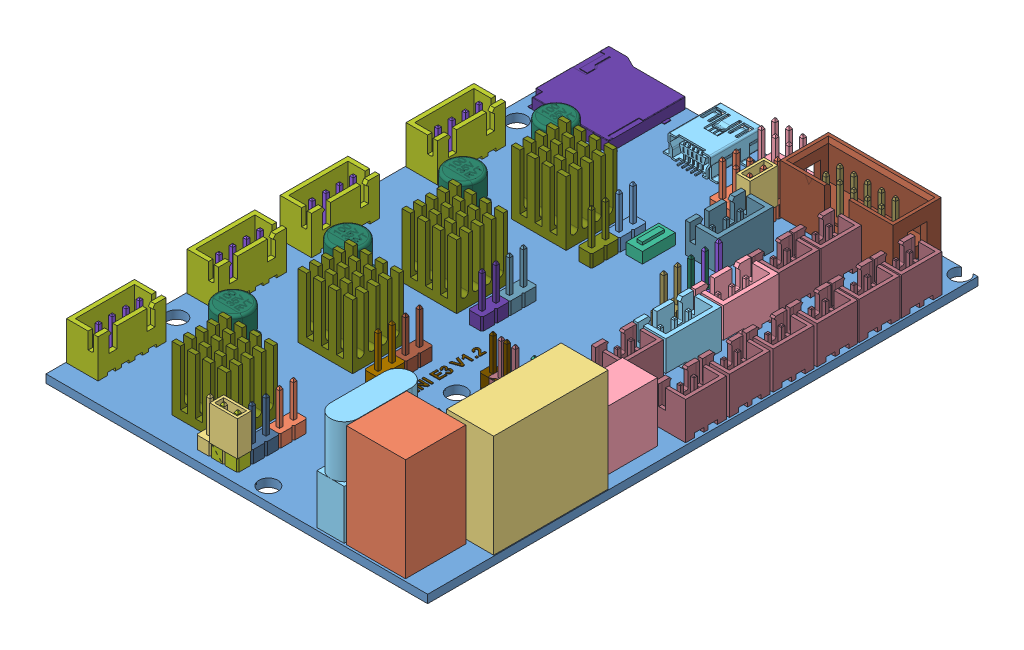
SolidWorks assembly BTT SKR MINI E3 V1.2 - 2020 DR.Phil3D v1, configuration BTT SKR MINI E3 V1.2 - 2020 DR.Phil3D v1. Lengths in mm.
Overall size (69.7 22.28 101.21).
95 component instances, 41 part files, 0 mates.
Components (placement in the parent):
- SKR Mini E3 1.2-1: SKR Mini E3 1.2 [SKR Mini E3 1.2] at (0.4313 -1.6126 -0.8701) size (69.7 20.32 100.5)
  - PCB-1: PCB [PCB] at origin size (69.7 1.5 100.5)
  - Power IN-1: Power IN [Power IN] at (-14.6583 0 -3.0665) size (10.79 18.82 11)
  - Power & Bed -1: Power & Bed  [Power & Bed ] at (-15.6583 0 -3.0665) size (8.58 18.82 20.9)
  - E0-1: E0 [E0] at (-15.6583 0 -3.0665) size (6.36 10.82 10)
  - Fuse-1: Fuse [Fuse] at (-14.6583 0 -3.0665) size (5 18.48 14.84)
  - Reset-1: Reset [Reset] at (-4.0633 0 9.9288) size (3 2.5 6)
- 4 pin Header-1: 4 pin Header [4 pin Header] at (-25.3481 -5.4688 -25.9996) x (0 0 1) z (-1 0 0) size (12.4 10.4 5.75)
  - B4B-XH-A (BODY)-1: B4B-XH-A (BODY) [B4B-XH-A (BODY)] at (1.9192 5.3562 13.8157) size (12.4 7 5.75)
  - B4B-XH-A (PIN)-1: B4B-XH-A (PIN) [B4B-XH-A (PIN)] at (5.6692 12.3562 13.2907) x (-1 0 0) z (0 0 1) size (0.64 10.4 0.64)
  - B4B-XH-A (PIN)-2: B4B-XH-A (PIN) [B4B-XH-A (PIN)] at (3.1692 12.3562 13.2907) x (-1 0 0) z (0 0 1) size (0.64 10.4 0.64)
  - B4B-XH-A (PIN)-3: B4B-XH-A (PIN) [B4B-XH-A (PIN)] at (0.6692 12.3562 13.2907) x (-1 0 0) z (0 0 1) size (0.64 10.4 0.64)
  - B4B-XH-A (PIN)-4: B4B-XH-A (PIN) [B4B-XH-A (PIN)] at (-1.8308 12.3562 13.2907) x (-1 0 0) z (0 0 1) size (0.64 10.4 0.64)
- 4 pin Header_1-1: 4 pin Header_1 [4 pin Header_1] at (-25.3481 -5.4688 -2.9996) x (0 0 1) z (-1 0 0) size (12.4 10.4 5.75)
  - B4B-XH-A (BODY)-1: B4B-XH-A (BODY) [B4B-XH-A (BODY)] at (1.9192 5.3562 13.8157) size (12.4 7 5.75)
  - B4B-XH-A (PIN)-1: B4B-XH-A (PIN) [B4B-XH-A (PIN)] at (5.6692 12.3562 13.2907) x (-1 0 0) z (0 0 1) size (0.64 10.4 0.64)
  - B4B-XH-A (PIN)-2: B4B-XH-A (PIN) [B4B-XH-A (PIN)] at (3.1692 12.3562 13.2907) x (-1 0 0) z (0 0 1) size (0.64 10.4 0.64)
  - B4B-XH-A (PIN)-3: B4B-XH-A (PIN) [B4B-XH-A (PIN)] at (0.6692 12.3562 13.2907) x (-1 0 0) z (0 0 1) size (0.64 10.4 0.64)
  - B4B-XH-A (PIN)-4: B4B-XH-A (PIN) [B4B-XH-A (PIN)] at (-1.8308 12.3562 13.2907) x (-1 0 0) z (0 0 1) size (0.64 10.4 0.64)
- 4 pin Header_2-1: 4 pin Header_2 [4 pin Header_2] at (-25.3481 -5.4688 14.0004) x (0 0 1) z (-1 0 0) size (12.4 10.4 5.75)
  - B4B-XH-A (BODY)-1: B4B-XH-A (BODY) [B4B-XH-A (BODY)] at (1.9192 5.3562 13.8157) size (12.4 7 5.75)
  - B4B-XH-A (PIN)-1: B4B-XH-A (PIN) [B4B-XH-A (PIN)] at (5.6692 12.3562 13.2907) x (-1 0 0) z (0 0 1) size (0.64 10.4 0.64)
  - B4B-XH-A (PIN)-2: B4B-XH-A (PIN) [B4B-XH-A (PIN)] at (3.1692 12.3562 13.2907) x (-1 0 0) z (0 0 1) size (0.64 10.4 0.64)
  - B4B-XH-A (PIN)-3: B4B-XH-A (PIN) [B4B-XH-A (PIN)] at (0.6692 12.3562 13.2907) x (-1 0 0) z (0 0 1) size (0.64 10.4 0.64)
  - B4B-XH-A (PIN)-4: B4B-XH-A (PIN) [B4B-XH-A (PIN)] at (-1.8308 12.3562 13.2907) x (-1 0 0) z (0 0 1) size (0.64 10.4 0.64)
- 4 pin Header_3-1: 4 pin Header_3 [4 pin Header_3] at (-25.3481 -5.4688 36.0004) x (0 0 1) z (-1 0 0) size (12.4 10.4 5.75)
  - B4B-XH-A (BODY)-1: B4B-XH-A (BODY) [B4B-XH-A (BODY)] at (1.9192 5.3562 13.8157) size (12.4 7 5.75)
  - B4B-XH-A (PIN)-1: B4B-XH-A (PIN) [B4B-XH-A (PIN)] at (5.6692 12.3562 13.2907) x (-1 0 0) z (0 0 1) size (0.64 10.4 0.64)
  - B4B-XH-A (PIN)-2: B4B-XH-A (PIN) [B4B-XH-A (PIN)] at (3.1692 12.3562 13.2907) x (-1 0 0) z (0 0 1) size (0.64 10.4 0.64)
  - B4B-XH-A (PIN)-3: B4B-XH-A (PIN) [B4B-XH-A (PIN)] at (0.6692 12.3562 13.2907) x (-1 0 0) z (0 0 1) size (0.64 10.4 0.64)
  - B4B-XH-A (PIN)-4: B4B-XH-A (PIN) [B4B-XH-A (PIN)] at (-1.8308 12.3562 13.2907) x (-1 0 0) z (0 0 1) size (0.64 10.4 0.64)
- 2 Pin connector (13)-1: 2 Pin connector (13) [2 Pin connector (13)] at (10.6557 -0.1126 28.8793) x (0 0 -1) z (1 0 0) size (5.08 11.94 2.54)
  - Component52-1: Component52 [Component52] at origin size (5.08 11.94 2.54)
- 2 Pin connector (19)-1: 2 Pin connector (19) [2 Pin connector (19)] at (8.1557 -0.1126 28.8793) x (0 0 -1) z (1 0 0) size (5.08 11.94 2.54)
  - Component53-1: Component53 [Component53] at origin size (5.08 11.94 2.54)
- DS1013-10SSiB v1-1: DS1013-10SSiB v1 [DS1013-10SSiB v1] at (5.7052 0 -46.8226) x (1 0 0) z (0 1 0) size (20.6 9.1 12.4)
  - body-1: body [body] at origin size (20.6 9.1 9.3)
  - pin-1: pin [pin] at origin size (0.64 0.64 11.5)
  - pin-2: pin [pin] at (2.54 0 0) size (0.64 0.64 11.5)
  - pin-3: pin [pin] at (5.08 0 0) size (0.64 0.64 11.5)
  - pin-4: pin [pin] at (7.62 0 0) size (0.64 0.64 11.5)
  - pin-5: pin [pin] at (0 2.54 0) size (0.64 0.64 11.5)
  - pin-6: pin [pin] at (2.54 2.54 0) size (0.64 0.64 11.5)
  - pin-7: pin [pin] at (5.08 2.54 0) size (0.64 0.64 11.5)
  - pin-8: pin [pin] at (7.62 2.54 0) size (0.64 0.64 11.5)
  - pin-9: pin [pin] at (10.16 0 0) size (0.64 0.64 11.5)
  - pin-10: pin [pin] at (10.16 2.54 0) size (0.64 0.64 11.5)
- JST 2pin-1: JST 2pin [JST 2pin] at (9.9082 -0.1126 -7.1947) x (-1 0 0) z (0 0 -1) size (5.73 10.3 7.43)
- Header 3 pin-1: Header 3 pin [Header 3 pin] at (1.8482 -0.1126 -33.0477) x (0 0 1) z (-1 0 0) size (10.16 7.2 5.9)
- 100uF 35V 6.3x7-1: 100uF 35V 6.3x7 [100uF 35V 6.3x7] at (-28.7944 0.8874 26.9674) x (-1 0 0) z (0 0 -1) size (6.66 7.76 7.2)
- TMC 2209 Heatsink-1: TMC 2209 Heatsink [TMC 2209 Heatsink] at (-21.6787 1.8374 38.0799) x (1 0 0) z (0 1 0) size (9.98 9.3 11.65)
- sdreader-1: sdreader [sdreader] at (-33.9687 -1.5126 -38.3866) x (0 0 1) z (0 1 0) size (15 16 2)
- Component14-1: Component14 [Component14] at origin size (1.85 0.1 25.79)
- Component15-1: Component15 [Component15] at origin size (0.73 0.1 6.6)
- 2 Pin connector-1: 2 Pin connector [2 Pin connector] at (-0.9803 -0.3666 -42.1218) x (0 0 1) z (-1 0 0) size (5.08 11.94 2.54)
- Jumper-1: Jumper [Jumper] at (-15.4835 0 -3.6239) size (2.55 6.35 5.06)
- Header 3 pin (1)-1: Header 3 pin (1) [Header 3 pin (1)] at (12.9215 -0.1126 -22.9838) x (0 0 1) z (-1 0 0) size (10.16 7.2 5.9)
- Header 3 pin (2)-1: Header 3 pin (2) [Header 3 pin (2)] at (12.9215 -0.1126 -12.4838) x (0 0 1) z (-1 0 0) size (10.16 7.2 5.9)
- 100uF 35V 6.3x7-2: 100uF 35V 6.3x7 [100uF 35V 6.3x7] at (-28.7944 0.8874 5.9674) x (-1 0 0) z (0 0 -1) size (6.66 7.76 7.2)
- TMC 2209 Heatsink-2: TMC 2209 Heatsink [TMC 2209 Heatsink] at (-21.6787 1.8374 15.0799) x (1 0 0) z (0 1 0) size (9.98 9.3 11.65)
- 100uF 35V 6.3x7-3: 100uF 35V 6.3x7 [100uF 35V 6.3x7] at (-28.7944 0.8874 -15.0326) x (-1 0 0) z (0 0 -1) size (6.66 7.76 7.2)
- TMC 2209 Heatsink-3: TMC 2209 Heatsink [TMC 2209 Heatsink] at (-21.6787 1.8374 -3.9201) x (1 0 0) z (0 1 0) size (9.98 9.3 11.65)
- 100uF 35V 6.3x7-4: 100uF 35V 6.3x7 [100uF 35V 6.3x7] at (-28.7944 0.8874 -32.0326) x (-1 0 0) z (0 0 -1) size (6.66 7.76 7.2)
- TMC 2209 Heatsink-4: TMC 2209 Heatsink [TMC 2209 Heatsink] at (-21.6787 1.8374 -23.9201) x (1 0 0) z (0 1 0) size (9.98 9.3 11.65)
- JST 2pin-2: JST 2pin [JST 2pin] at (9.9082 -0.1126 -35.6947) x (-1 0 0) z (0 0 -1) size (5.73 10.3 7.43)
- JST 2pin-3: JST 2pin [JST 2pin] at (9.9082 -0.1126 -43.3829) x (-1 0 0) z (0 0 -1) size (5.73 10.3 7.43)
- JST 2pin-4: JST 2pin [JST 2pin] at (21.4082 -0.1126 -7.1947) x (-1 0 0) z (0 0 -1) size (5.73 10.3 7.43)
- JST 2pin-5: JST 2pin [JST 2pin] at (21.4082 -0.1126 -38.8829) x (-1 0 0) z (0 0 -1) size (5.73 10.3 7.43)
- JST 2pin-6: JST 2pin [JST 2pin] at (21.4082 -0.1126 -15.1947) x (-1 0 0) z (0 0 -1) size (5.73 10.3 7.43)
- JST 2pin-7: JST 2pin [JST 2pin] at (21.4082 -0.1126 -23.1947) x (-1 0 0) z (0 0 -1) size (5.73 10.3 7.43)
- JST 2pin-8: JST 2pin [JST 2pin] at (21.4082 -0.1126 -31.1947) x (-1 0 0) z (0 0 -1) size (5.73 10.3 7.43)
- JST 2pin-9: JST 2pin [JST 2pin] at (21.4082 -0.1126 -46.5829) x (-1 0 0) z (0 0 -1) size (5.73 10.3 7.43)
- 2 Pin connector-2: 2 Pin connector [2 Pin connector] at (-3.4803 -0.3666 -42.1218) x (0 0 1) z (-1 0 0) size (5.08 11.94 2.54)
- 2 Pin connector-3: 2 Pin connector [2 Pin connector] at (-5.9803 -0.3666 -42.1218) x (0 0 1) z (-1 0 0) size (5.08 11.94 2.54)
- 2 Pin connector-4: 2 Pin connector [2 Pin connector] at (-0.9803 -0.3666 -44.6618) x (0 0 1) z (-1 0 0) size (5.08 11.94 2.54)
- Jumper-2: Jumper [Jumper] at (-48.7447 0 30.2029) x (0 0 1) z (-1 0 0) size (2.55 6.35 5.06)
- 2 Pin connector (5)-1: 2 Pin connector (5) [2 Pin connector (5)] at (11.0313 -0.1126 9.1899) x (-1 0 0) z (0 0 -1) size (5.08 11.94 2.54)
- 2 Pin connector (11)-1: 2 Pin connector (11) [2 Pin connector (11)] at (-10.2712 -0.3666 44.6158) x (-1 0 0) z (0 0 -1) size (5.08 11.94 2.54)
- 2 Pin connector (12)-1: 2 Pin connector (12) [2 Pin connector (12)] at (6.8963 -0.1126 -23.5114) x (0 0 -1) z (1 0 0) size (5.08 11.94 2.54)
- 2 Pin connector (14)-1: 2 Pin connector (14) [2 Pin connector (14)] at (-10.2606 -0.3666 16.4669) x (0 0 1) z (-1 0 0) size (5.08 11.94 2.54)
- 2 Pin connector (15)-1: 2 Pin connector (15) [2 Pin connector (15)] at (-10.2606 -0.3666 39.4669) x (0 0 1) z (-1 0 0) size (5.08 11.94 2.54)
- 2 Pin connector (16)-1: 2 Pin connector (16) [2 Pin connector (16)] at (-10.2606 -0.3666 11.4669) x (0 0 1) z (-1 0 0) size (5.08 11.94 2.54)
- 2 Pin connector (17)-1: 2 Pin connector (17) [2 Pin connector (17)] at (6.8963 -0.1126 -16.0114) x (0 0 -1) z (1 0 0) size (5.08 11.94 2.54)
- 2 Pin connector (18)-1: 2 Pin connector (18) [2 Pin connector (18)] at (5.0143 -0.1126 9.2211) x (-1 0 0) z (0 0 -1) size (5.08 11.94 2.54)
- 2 Pin connector (20)-1: 2 Pin connector (20) [2 Pin connector (20)] at (-10.2606 -0.3666 -7.5331) x (0 0 1) z (-1 0 0) size (5.08 11.94 2.54)
- 2 Pin connector (21)-1: 2 Pin connector (21) [2 Pin connector (21)] at (6.8963 -0.1126 -21.0114) x (0 0 -1) z (1 0 0) size (5.08 11.94 2.54)
- 2 Pin connector (22)-1: 2 Pin connector (22) [2 Pin connector (22)] at (-10.2606 -0.3666 -22.5331) x (0 0 1) z (-1 0 0) size (5.08 11.94 2.54)
- 2 Pin connector (23)-1: 2 Pin connector (23) [2 Pin connector (23)] at (-10.2606 -0.3666 -2.5331) x (0 0 1) z (-1 0 0) size (5.08 11.94 2.54)
- 2 Pin connector (24)-1: 2 Pin connector (24) [2 Pin connector (24)] at (3.4513 -0.1126 9.1899) x (-1 0 0) z (0 0 -1) size (5.08 11.94 2.54)
- 2 Pin connector (25)-1: 2 Pin connector (25) [2 Pin connector (25)] at (-10.2606 -0.3666 -27.5331) x (0 0 1) z (-1 0 0) size (5.08 11.94 2.54)
- 2 Pin connector (26)-1: 2 Pin connector (26) [2 Pin connector (26)] at (-10.2606 -0.3666 34.4669) x (0 0 1) z (-1 0 0) size (5.08 11.94 2.54)
- 2 Pin connector (27)-1: 2 Pin connector (27) [2 Pin connector (27)] at (-12.7712 -0.3666 44.6158) x (-1 0 0) z (0 0 -1) size (5.08 11.94 2.54)
- zl201-3_p2-54_l7-62_w2-54_h8-89 v1-1: zl201-3_p2-54_l7-62_w2-54_h8-89 v1 [zl201-3_p2-54_l7-62_w2-54_h8-89 v1] at (-7.1165 -0.1 -47.85) size (7.62 11.94 2.54)
- zl201-3_p2-54_l7-62_w2-54_h8-89 v1-2: zl201-3_p2-54_l7-62_w2-54_h8-89 v1 [zl201-3_p2-54_l7-62_w2-54_h8-89 v1] at (-7.1165 -0.1 -50.35) size (7.62 11.94 2.54)
- USB_MINI_B_SMD v35 v1-1: USB_MINI_B_SMD v35 v1 [USB_MINI_B_SMD v35 v1] at (-15.7973 -0.1 -52.75) x (-1 0 0) z (0 0 -1) size (9.9 4.19 9.9)
